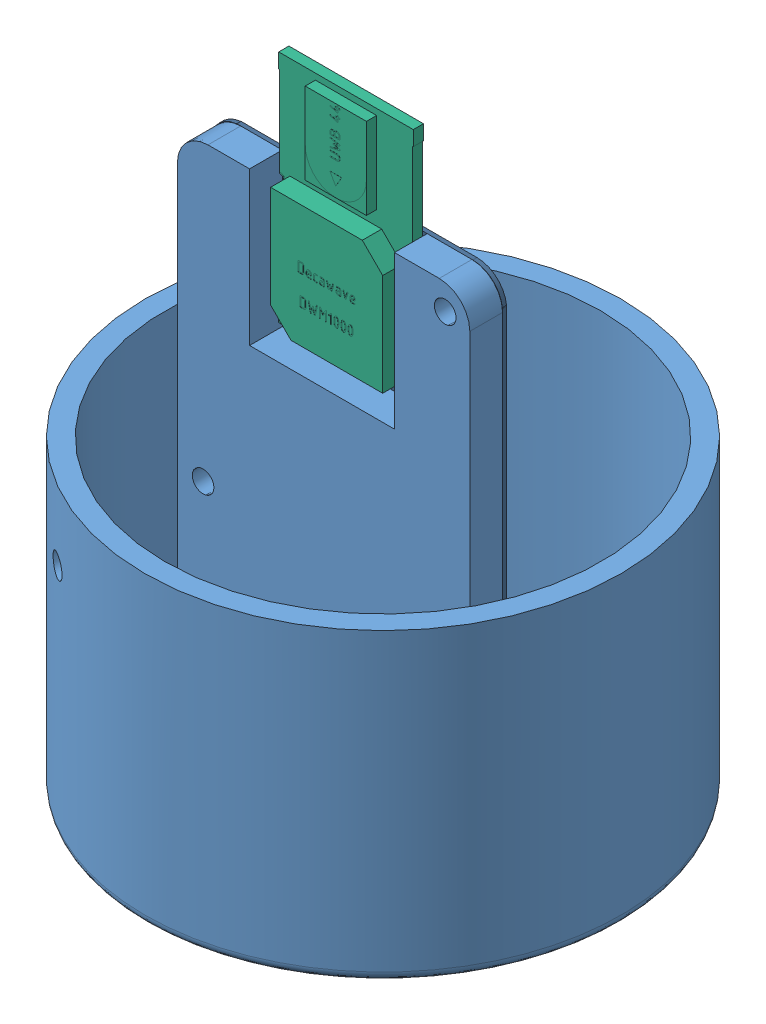
SolidWorks assembly 机器人顶部UWB基站装配, configuration 默认. Lengths in mm.
Overall size (46.7 61.16 46.7).
233 component instances, 28 part files, 0 mates.
Components (placement in the parent):
- UWB天线支架-TWR-1: UWB天线支架-TWR [默认] at (-22.1271 -22.7514 62) size (46.7 52 46.7)
- GeekUWB-TWR.step-1: GeekUWB-TWR.step [默认] at (68.161 -75.1454 64.2043) x (-1 0 0) z (0 0 -1) size (28.7 41.1 6.58)
  - R14.step-1: R14.step [默认] at origin size (0.5 1 0.35)
    - 5863272896.step-1: 5863272896.step [默认] at (77.2159 80.1371 0) x (0 1 0) z (0 0 1) size (1 0.5 0.35)
      - Terminal.step-1: Terminal.step [默认] at (-0.5 -0.25 0) size (0.25 0.5 0.35)
        - Open_CASCADE_STEP_translator_6.8_20.2.1.step-1: Open_CASCADE_STEP_translator_6.8_20.2.1.step [默认] at origin size (0.25 0.5 0.35)
      - Terminal.step-2: Terminal.step [默认] at (0.5 0.25 0) x (-1 0 0) z (0 0 1) size (0.25 0.5 0.35)
        - Open_CASCADE_STEP_translator_6.8_20.2.1.step-1: Open_CASCADE_STEP_translator_6.8_20.2.1.step [默认] at origin size (0.25 0.5 0.35)
      - Mid_Body.step-1: Mid_Body.step [默认] at (-0.5 -0.25 0) size (0.93 0.5 0.28)
      - Mark.step-1: Mark.step [默认] at (-0.25 -0.25 0.315) size (0.5 0.5 0.03)
  - C7.step-1: C7.step [默认] at origin size (1 0.5 0.5)
    - 5863272512.step-1: 5863272512.step [默认] at (78.8669 91.4399 0) x (-1 0 0) z (0 0 1) size (1 0.5 0.5)
      - Terminal-1.step-1: Terminal-1.step [默认] at (-0.5 -0.25 0) size (1 0.5 0.5)
        - Open_CASCADE_STEP_translator_6.8_54.1.1.step-1: Open_CASCADE_STEP_translator_6.8_54.1.1.step [默认] at origin size (0.25 0.5 0.5)
        - Open_CASCADE_STEP_translator_6.8_54.1.2.step-1: Open_CASCADE_STEP_translator_6.8_54.1.2.step [默认] at origin size (0.25 0.5 0.5)
      - Mid_Body-0.step-1: Mid_Body-0.step [默认] at (-0.5 -0.25 0) size (0.5 0.5 0.5)
        - Open_CASCADE_STEP_translator_6.8_54.2.1.step-1: Open_CASCADE_STEP_translator_6.8_54.2.1.step [默认] at origin size (0.5 0.5 0.5)
  - Y1.step-1: Y1.step [默认] at origin size (1.31 3.21 0.71)
    - 123123123.step-1: 123123123.step [默认] at (79.121 88.3921 0) x (0 1 0) z (0 0 1) size (3.21 1.31 0.71)
  - R7.step-1: R7.step [默认] at origin size (1 0.5 0.35)
    - 5863271360.step-1: 5863271360.step [默认] at (88.0109 97.2819 0) x (-1 0 0) z (0 0 1) size (1 0.5 0.35)
      - Terminal-2.step-1: Terminal-2.step [默认] at (-0.5 -0.25 0) size (0.25 0.5 0.35)
        - Open_CASCADE_STEP_translator_6.8_20.2.1-1.step-1: Open_CASCADE_STEP_translator_6.8_20.2.1-1.step [默认] at origin size (0.25 0.5 0.35)
      - Terminal-2.step-2: Terminal-2.step [默认] at (0.5 0.25 0) x (-1 0 0) z (0 0 1) size (0.25 0.5 0.35)
        - Open_CASCADE_STEP_translator_6.8_20.2.1-1.step-1: Open_CASCADE_STEP_translator_6.8_20.2.1-1.step [默认] at origin size (0.25 0.5 0.35)
      - Mid_Body-2.step-1: Mid_Body-2.step [默认] at (-0.5 -0.25 0) size (0.93 0.5 0.28)
      - Mark-3.step-1: Mark-3.step [默认] at (-0.25 -0.25 0.315) size (0.5 0.5 0.03)
  - R10.step-1: R10.step [默认] at origin size (1 0.5 0.35)
    - 5863271744.step-1: 5863271744.step [默认] at (101.3461 99.0601 0) x (1 0 0) z (0 0 1) size (1 0.5 0.35)
      - Terminal-3.step-1: Terminal-3.step [默认] at (-0.5 -0.25 0) size (0.25 0.5 0.35)
        - Open_CASCADE_STEP_translator_6.8_20.2.1-4.step-1: Open_CASCADE_STEP_translator_6.8_20.2.1-4.step [默认] at origin size (0.25 0.5 0.35)
      - Terminal-3.step-2: Terminal-3.step [默认] at (0.5 0.25 0) x (-1 0 0) z (0 0 1) size (0.25 0.5 0.35)
        - Open_CASCADE_STEP_translator_6.8_20.2.1-4.step-1: Open_CASCADE_STEP_translator_6.8_20.2.1-4.step [默认] at origin size (0.25 0.5 0.35)
      - Mid_Body-5.step-1: Mid_Body-5.step [默认] at (-0.5 -0.25 0) size (0.93 0.5 0.28)
      - Mark-6.step-1: Mark-6.step [默认] at (-0.25 -0.25 0.315) size (0.5 0.5 0.03)
  - R9.step-1: R9.step [默认] at origin size (1 0.5 0.35)
    - 5863271744.step-1: 5863271744.step [默认] at (101.3461 100.2031 0) x (1 0 0) z (0 0 1) size (1 0.5 0.35)
      - Terminal-3.step-1: Terminal-3.step [默认] at (-0.5 -0.25 0) size (0.25 0.5 0.35)
        - Open_CASCADE_STEP_translator_6.8_20.2.1-4.step-1: Open_CASCADE_STEP_translator_6.8_20.2.1-4.step [默认] at origin size (0.25 0.5 0.35)
      - Terminal-3.step-2: Terminal-3.step [默认] at (0.5 0.25 0) x (-1 0 0) z (0 0 1) size (0.25 0.5 0.35)
        - Open_CASCADE_STEP_translator_6.8_20.2.1-4.step-1: Open_CASCADE_STEP_translator_6.8_20.2.1-4.step [默认] at origin size (0.25 0.5 0.35)
      - Mid_Body-5.step-1: Mid_Body-5.step [默认] at (-0.5 -0.25 0) size (0.93 0.5 0.28)
      - Mark-6.step-1: Mark-6.step [默认] at (-0.25 -0.25 0.315) size (0.5 0.5 0.03)
  - R8.step-1: R8.step [默认] at origin size (1 0.5 0.35)
    - 5863271360.step-1: 5863271360.step [默认] at (82.0419 87.8839 0) x (-1 0 0) z (0 0 1) size (1 0.5 0.35)
      - Terminal-2.step-1: Terminal-2.step [默认] at (-0.5 -0.25 0) size (0.25 0.5 0.35)
        - Open_CASCADE_STEP_translator_6.8_20.2.1-1.step-1: Open_CASCADE_STEP_translator_6.8_20.2.1-1.step [默认] at origin size (0.25 0.5 0.35)
      - Terminal-2.step-2: Terminal-2.step [默认] at (0.5 0.25 0) x (-1 0 0) z (0 0 1) size (0.25 0.5 0.35)
        - Open_CASCADE_STEP_translator_6.8_20.2.1-1.step-1: Open_CASCADE_STEP_translator_6.8_20.2.1-1.step [默认] at origin size (0.25 0.5 0.35)
      - Mid_Body-2.step-1: Mid_Body-2.step [默认] at (-0.5 -0.25 0) size (0.93 0.5 0.28)
      - Mark-3.step-1: Mark-3.step [默认] at (-0.25 -0.25 0.315) size (0.5 0.5 0.03)
  - R6.step-1: R6.step [默认] at origin size (1 0.5 0.35)
    - 5863271744.step-1: 5863271744.step [默认] at (100.7111 89.2811 0) x (1 0 0) z (0 0 1) size (1 0.5 0.35)
      - Terminal-3.step-1: Terminal-3.step [默认] at (-0.5 -0.25 0) size (0.25 0.5 0.35)
        - Open_CASCADE_STEP_translator_6.8_20.2.1-4.step-1: Open_CASCADE_STEP_translator_6.8_20.2.1-4.step [默认] at origin size (0.25 0.5 0.35)
      - Terminal-3.step-2: Terminal-3.step [默认] at (0.5 0.25 0) x (-1 0 0) z (0 0 1) size (0.25 0.5 0.35)
        - Open_CASCADE_STEP_translator_6.8_20.2.1-4.step-1: Open_CASCADE_STEP_translator_6.8_20.2.1-4.step [默认] at origin size (0.25 0.5 0.35)
      - Mid_Body-5.step-1: Mid_Body-5.step [默认] at (-0.5 -0.25 0) size (0.93 0.5 0.28)
      - Mark-6.step-1: Mark-6.step [默认] at (-0.25 -0.25 0.315) size (0.5 0.5 0.03)
  - R5.step-1: R5.step [默认] at origin size (1 0.5 0.35)
    - 5863271744.step-1: 5863271744.step [默认] at (101.3461 101.3461 0) x (1 0 0) z (0 0 1) size (1 0.5 0.35)
      - Terminal-3.step-1: Terminal-3.step [默认] at (-0.5 -0.25 0) size (0.25 0.5 0.35)
        - Open_CASCADE_STEP_translator_6.8_20.2.1-4.step-1: Open_CASCADE_STEP_translator_6.8_20.2.1-4.step [默认] at origin size (0.25 0.5 0.35)
      - Terminal-3.step-2: Terminal-3.step [默认] at (0.5 0.25 0) x (-1 0 0) z (0 0 1) size (0.25 0.5 0.35)
        - Open_CASCADE_STEP_translator_6.8_20.2.1-4.step-1: Open_CASCADE_STEP_translator_6.8_20.2.1-4.step [默认] at origin size (0.25 0.5 0.35)
      - Mid_Body-5.step-1: Mid_Body-5.step [默认] at (-0.5 -0.25 0) size (0.93 0.5 0.28)
      - Mark-6.step-1: Mark-6.step [默认] at (-0.25 -0.25 0.315) size (0.5 0.5 0.03)
  - R2.step-1: R2.step [默认] at origin size (1 0.5 0.35)
    - 5863271744.step-1: 5863271744.step [默认] at (80.8991 85.4711 0) x (1 0 0) z (0 0 1) size (1 0.5 0.35)
      - Terminal-3.step-1: Terminal-3.step [默认] at (-0.5 -0.25 0) size (0.25 0.5 0.35)
        - Open_CASCADE_STEP_translator_6.8_20.2.1-4.step-1: Open_CASCADE_STEP_translator_6.8_20.2.1-4.step [默认] at origin size (0.25 0.5 0.35)
      - Terminal-3.step-2: Terminal-3.step [默认] at (0.5 0.25 0) x (-1 0 0) z (0 0 1) size (0.25 0.5 0.35)
        - Open_CASCADE_STEP_translator_6.8_20.2.1-4.step-1: Open_CASCADE_STEP_translator_6.8_20.2.1-4.step [默认] at origin size (0.25 0.5 0.35)
      - Mid_Body-5.step-1: Mid_Body-5.step [默认] at (-0.5 -0.25 0) size (0.93 0.5 0.28)
      - Mark-6.step-1: Mark-6.step [默认] at (-0.25 -0.25 0.315) size (0.5 0.5 0.03)
  - R3.step-1: R3.step [默认] at origin size (1 0.5 0.35)
    - 5863271744.step-1: 5863271744.step [默认] at (80.8991 84.4551 0) x (1 0 0) z (0 0 1) size (1 0.5 0.35)
      - Terminal-3.step-1: Terminal-3.step [默认] at (-0.5 -0.25 0) size (0.25 0.5 0.35)
        - Open_CASCADE_STEP_translator_6.8_20.2.1-4.step-1: Open_CASCADE_STEP_translator_6.8_20.2.1-4.step [默认] at origin size (0.25 0.5 0.35)
      - Terminal-3.step-2: Terminal-3.step [默认] at (0.5 0.25 0) x (-1 0 0) z (0 0 1) size (0.25 0.5 0.35)
        - Open_CASCADE_STEP_translator_6.8_20.2.1-4.step-1: Open_CASCADE_STEP_translator_6.8_20.2.1-4.step [默认] at origin size (0.25 0.5 0.35)
      - Mid_Body-5.step-1: Mid_Body-5.step [默认] at (-0.5 -0.25 0) size (0.93 0.5 0.28)
      - Mark-6.step-1: Mark-6.step [默认] at (-0.25 -0.25 0.315) size (0.5 0.5 0.03)
  - R1.step-1: R1.step [默认] at origin size (0.5 1 0.35)
    - 5863272896.step-1: 5863272896.step [默认] at (78.294 80.1531 0) x (0 1 0) z (0 0 1) size (1 0.5 0.35)
      - Terminal.step-1: Terminal.step [默认] at (-0.5 -0.25 0) size (0.25 0.5 0.35)
        - Open_CASCADE_STEP_translator_6.8_20.2.1.step-1: Open_CASCADE_STEP_translator_6.8_20.2.1.step [默认] at origin size (0.25 0.5 0.35)
      - Terminal.step-2: Terminal.step [默认] at (0.5 0.25 0) x (-1 0 0) z (0 0 1) size (0.25 0.5 0.35)
        - Open_CASCADE_STEP_translator_6.8_20.2.1.step-1: Open_CASCADE_STEP_translator_6.8_20.2.1.step [默认] at origin size (0.25 0.5 0.35)
      - Mid_Body.step-1: Mid_Body.step [默认] at (-0.5 -0.25 0) size (0.93 0.5 0.28)
      - Mark.step-1: Mark.step [默认] at (-0.25 -0.25 0.315) size (0.5 0.5 0.03)
  - R4.step-1: R4.step [默认] at origin size (1 0.5 0.35)
    - 5863271744.step-1: 5863271744.step [默认] at (80.8991 83.4391 0) x (1 0 0) z (0 0 1) size (1 0.5 0.35)
      - Terminal-3.step-1: Terminal-3.step [默认] at (-0.5 -0.25 0) size (0.25 0.5 0.35)
        - Open_CASCADE_STEP_translator_6.8_20.2.1-4.step-1: Open_CASCADE_STEP_translator_6.8_20.2.1-4.step [默认] at origin size (0.25 0.5 0.35)
      - Terminal-3.step-2: Terminal-3.step [默认] at (0.5 0.25 0) x (-1 0 0) z (0 0 1) size (0.25 0.5 0.35)
        - Open_CASCADE_STEP_translator_6.8_20.2.1-4.step-1: Open_CASCADE_STEP_translator_6.8_20.2.1-4.step [默认] at origin size (0.25 0.5 0.35)
      - Mid_Body-5.step-1: Mid_Body-5.step [默认] at (-0.5 -0.25 0) size (0.93 0.5 0.28)
      - Mark-6.step-1: Mark-6.step [默认] at (-0.25 -0.25 0.315) size (0.5 0.5 0.03)
  - R13.step-1: R13.step [默认] at origin size (1 0.5 0.35)
    - 5863271360.step-1: 5863271360.step [默认] at (98.8059 91.4399 0) x (-1 0 0) z (0 0 1) size (1 0.5 0.35)
      - Terminal-2.step-1: Terminal-2.step [默认] at (-0.5 -0.25 0) size (0.25 0.5 0.35)
        - Open_CASCADE_STEP_translator_6.8_20.2.1-1.step-1: Open_CASCADE_STEP_translator_6.8_20.2.1-1.step [默认] at origin size (0.25 0.5 0.35)
      - Terminal-2.step-2: Terminal-2.step [默认] at (0.5 0.25 0) x (-1 0 0) z (0 0 1) size (0.25 0.5 0.35)
        - Open_CASCADE_STEP_translator_6.8_20.2.1-1.step-1: Open_CASCADE_STEP_translator_6.8_20.2.1-1.step [默认] at origin size (0.25 0.5 0.35)
      - Mid_Body-2.step-1: Mid_Body-2.step [默认] at (-0.5 -0.25 0) size (0.93 0.5 0.28)
      - Mark-3.step-1: Mark-3.step [默认] at (-0.25 -0.25 0.315) size (0.5 0.5 0.03)
  - R12.step-1: R12.step [默认] at origin size (0.5 1 0.35)
    - 5863271552.step-1: 5863271552.step [默认] at (101.2191 86.7769 0) x (0 -1 0) z (0 0 1) size (1 0.5 0.35)
      - Terminal-4.step-1: Terminal-4.step [默认] at (-0.5 -0.25 0) size (0.25 0.5 0.35)
        - Open_CASCADE_STEP_translator_6.8_20.2.1-7.step-1: Open_CASCADE_STEP_translator_6.8_20.2.1-7.step [默认] at origin size (0.25 0.5 0.35)
      - Terminal-4.step-2: Terminal-4.step [默认] at (0.5 0.25 0) x (-1 0 0) z (0 0 1) size (0.25 0.5 0.35)
        - Open_CASCADE_STEP_translator_6.8_20.2.1-7.step-1: Open_CASCADE_STEP_translator_6.8_20.2.1-7.step [默认] at origin size (0.25 0.5 0.35)
      - Mid_Body-8.step-1: Mid_Body-8.step [默认] at (-0.5 -0.25 0) size (0.93 0.5 0.28)
      - Mark-9.step-1: Mark-9.step [默认] at (-0.25 -0.25 0.315) size (0.5 0.5 0.03)
  - R11.step-1: R11.step [默认] at origin size (1 0.5 0.35)
    - 5863271744.step-1: 5863271744.step [默认] at (90.9941 97.3479 0) x (1 0 0) z (0 0 1) size (1 0.5 0.35)
      - Terminal-3.step-1: Terminal-3.step [默认] at (-0.5 -0.25 0) size (0.25 0.5 0.35)
        - Open_CASCADE_STEP_translator_6.8_20.2.1-4.step-1: Open_CASCADE_STEP_translator_6.8_20.2.1-4.step [默认] at origin size (0.25 0.5 0.35)
      - Terminal-3.step-2: Terminal-3.step [默认] at (0.5 0.25 0) x (-1 0 0) z (0 0 1) size (0.25 0.5 0.35)
        - Open_CASCADE_STEP_translator_6.8_20.2.1-4.step-1: Open_CASCADE_STEP_translator_6.8_20.2.1-4.step [默认] at origin size (0.25 0.5 0.35)
      - Mid_Body-5.step-1: Mid_Body-5.step [默认] at (-0.5 -0.25 0) size (0.93 0.5 0.28)
      - Mark-6.step-1: Mark-6.step [默认] at (-0.25 -0.25 0.315) size (0.5 0.5 0.03)
  - D4.step-1: D4.step [默认] at origin size (1.01 0.5 0.45)
    - User_Library-led_0402LED0402_red_.step-1: User_Library-led_0402LED0402_red_.step [默认] at (98.6791 89.281 0) x (1 0 0) z (0 0 1) size (1.01 0.5 0.45)
  - D1.step-1: D1.step [默认] at origin size (1.01 0.5 0.45)
    - User_Library-led_0402LED0402_red_.step-1: User_Library-led_0402LED0402_red_.step [默认] at (99.3141 100.203 0) x (1 0 0) z (0 0 1) size (1.01 0.5 0.45)
  - D2.step-1: D2.step [默认] at origin size (1.01 0.5 0.45)
    - User_Library-led_0402LED0402_red_.step-1: User_Library-led_0402LED0402_red_.step [默认] at (99.3141 99.06 0) x (1 0 0) z (0 0 1) size (1.01 0.5 0.45)
  - D3.step-1: D3.step [默认] at origin size (1.01 0.5 0.45)
    - User_Library-led_0402LED0402_red_.step-1: User_Library-led_0402LED0402_red_.step [默认] at (99.3141 101.346 0) x (1 0 0) z (0 0 1) size (1.01 0.5 0.45)
  - C5.step-1: C5.step [默认] at origin size (0.5 1 0.5)
    - 5863270784.step-1: 5863270784.step [默认] at (98.6791 96.5199 0) x (0 -1 0) z (0 0 1) size (1 0.5 0.5)
      - Terminal-5.step-1: Terminal-5.step [默认] at (-0.5 -0.25 0) size (1 0.5 0.5)
        - Open_CASCADE_STEP_translator_6.8_54.1.1-10.step-1: Open_CASCADE_STEP_translator_6.8_54.1.1-10.step [默认] at origin size (0.25 0.5 0.5)
        - Open_CASCADE_STEP_translator_6.8_54.1.2-11.step-1: Open_CASCADE_STEP_translator_6.8_54.1.2-11.step [默认] at origin size (0.25 0.5 0.5)
      - Mid_Body-1.step-1: Mid_Body-1.step [默认] at (-0.5 -0.25 0) size (0.5 0.5 0.5)
        - Open_CASCADE_STEP_translator_6.8_54.2.1-12.step-1: Open_CASCADE_STEP_translator_6.8_54.2.1-12.step [默认] at origin size (0.5 0.5 0.5)
  - C6.step-1: C6.step [默认] at origin size (1 0.5 0.5)
    - 5863272512.step-1: 5863272512.step [默认] at (82.0419 88.9126 0) x (-1 0 0) z (0 0 1) size (1 0.5 0.5)
      - Terminal-1.step-1: Terminal-1.step [默认] at (-0.5 -0.25 0) size (1 0.5 0.5)
        - Open_CASCADE_STEP_translator_6.8_54.1.1.step-1: Open_CASCADE_STEP_translator_6.8_54.1.1.step [默认] at origin size (0.25 0.5 0.5)
        - Open_CASCADE_STEP_translator_6.8_54.1.2.step-1: Open_CASCADE_STEP_translator_6.8_54.1.2.step [默认] at origin size (0.25 0.5 0.5)
      - Mid_Body-0.step-1: Mid_Body-0.step [默认] at (-0.5 -0.25 0) size (0.5 0.5 0.5)
        - Open_CASCADE_STEP_translator_6.8_54.2.1.step-1: Open_CASCADE_STEP_translator_6.8_54.2.1.step [默认] at origin size (0.5 0.5 0.5)
  - C4.step-1: C4.step [默认] at origin size (1.6 0.81 0.81)
    - C0603_3D.step-1: C0603_3D.step [默认] at (100.7109 96.3929 0) x (-1 0 0) z (0 0 1) size (1.6 0.81 0.81)
  - C3.step-1: C3.step [默认] at origin size (0.5 1 0.5)
    - 5863270784.step-1: 5863270784.step [默认] at (100.0761 86.7849 0) x (0 -1 0) z (0 0 1) size (1 0.5 0.5)
      - Terminal-5.step-1: Terminal-5.step [默认] at (-0.5 -0.25 0) size (1 0.5 0.5)
        - Open_CASCADE_STEP_translator_6.8_54.1.1-10.step-1: Open_CASCADE_STEP_translator_6.8_54.1.1-10.step [默认] at origin size (0.25 0.5 0.5)
        - Open_CASCADE_STEP_translator_6.8_54.1.2-11.step-1: Open_CASCADE_STEP_translator_6.8_54.1.2-11.step [默认] at origin size (0.25 0.5 0.5)
      - Mid_Body-1.step-1: Mid_Body-1.step [默认] at (-0.5 -0.25 0) size (0.5 0.5 0.5)
        - Open_CASCADE_STEP_translator_6.8_54.2.1-12.step-1: Open_CASCADE_STEP_translator_6.8_54.2.1-12.step [默认] at origin size (0.5 0.5 0.5)
  - C2.step-1: C2.step [默认] at origin size (0.81 1.6 0.81)
    - C0603_3D.step-1: C0603_3D.step [默认] at (98.5521 86.9949 0) x (0 -1 0) z (0 0 1) size (1.6 0.81 0.81)
  - C1.step-1: C1.step [默认] at origin size (1.6 0.81 0.81)
    - C0603_3D.step-1: C0603_3D.step [默认] at (78.9939 92.8369 0) x (-1 0 0) z (0 0 1) size (1.6 0.81 0.81)
  - USB.step-1: USB.step [默认] at origin size (8.96 7.76 4.27)
    - 1.step-1: 1.step [默认] at (98.1049 122.7063 3.5) x (1 0 0) z (0 0 -1) size (8.96 7.76 4.27)
  - U3.step-1: U3.step [默认] at origin size (13.2 23 2.9)
    - DWM1000_Module.step-1: DWM1000_Module.step [默认] at (90.301 102.0509 -0.4115) x (-1 0 0) z (0 -1 0) size (13.2 2.9 23)
  - U2.step-1: U2.step [默认] at origin size (2.9 2.8 1.2)
    - PCB1.step-1: PCB1.step [默认] at (80.4724 95.505 0) x (0 1 0) z (0 0 1) size (2.8 2.9 1.2)
  - U1.step-1: U1.step [默认] at origin size (12.01 12.01 1.45)
    - LQFP64-10x10.step-1: LQFP64-10x10.step [默认] at (90.2971 89.5349 0) x (0 -1 0) z (0 0 1) size (12.01 12.01 1.45)
      - LQFP64-10X10_1_AF0_ASM.step-1: LQFP64-10X10_1_AF0_ASM.step [默认] at origin size (12.01 12.01 1.45)
        - _0_25_100.step-1: _0_25_100.step [默认] at (-5 2.75 0.75) x (0 1 0) z (0 0 1) size (0.25 1 0.8)
        - _0_25_100.step-2: _0_25_100.step [默认] at (5 -1.25 0.75) x (0 -1 0) z (0 0 1) size (0.25 1 0.8)
        - _0_25_100.step-3: _0_25_100.step [默认] at (-0.75 5 0.75) size (0.25 1 0.8)
        - _0_25_100.step-4: _0_25_100.step [默认] at (-5 -2.75 0.75) x (0 1 0) z (0 0 1) size (0.25 1 0.8)
        - _0_25_100.step-5: _0_25_100.step [默认] at (-2.75 -5 0.75) x (-1 0 0) z (0 0 1) size (0.25 1 0.8)
        - _0_25_100.step-6: _0_25_100.step [默认] at (2.75 -5 0.75) x (-1 0 0) z (0 0 1) size (0.25 1 0.8)
        - _0_25_100.step-7: _0_25_100.step [默认] at (-5 3.75 0.75) x (0 1 0) z (0 0 1) size (0.25 1 0.8)
        - _0_25_100.step-8: _0_25_100.step [默认] at (5 -2.25 0.75) x (0 -1 0) z (0 0 1) size (0.25 1 0.8)
        - _0_25_100.step-9: _0_25_100.step [默认] at (0.25 5 0.75) size (0.25 1 0.8)
        - _0_25_100.step-10: _0_25_100.step [默认] at (-5 -1.75 0.75) x (0 1 0) z (0 0 1) size (0.25 1 0.8)
        - _0_25_100.step-11: _0_25_100.step [默认] at (5 3.25 0.75) x (0 -1 0) z (0 0 1) size (0.25 1 0.8)
        - _0_25_100.step-12: _0_25_100.step [默认] at (-0.25 -5 0.75) x (-1 0 0) z (0 0 1) size (0.25 1 0.8)
        - _0_25_100.step-13: _0_25_100.step [默认] at (5 -3.25 0.75) x (0 -1 0) z (0 0 1) size (0.25 1 0.8)
        - _0_25_100.step-14: _0_25_100.step [默认] at (1.25 5 0.75) size (0.25 1 0.8)
        - _0_25_100.step-15: _0_25_100.step [默认] at (-5 -0.75 0.75) x (0 1 0) z (0 0 1) size (0.25 1 0.8)
        - _0_25_100.step-16: _0_25_100.step [默认] at (5 2.25 0.75) x (0 -1 0) z (0 0 1) size (0.25 1 0.8)
        - _0_25_100.step-17: _0_25_100.step [默认] at (-3.25 -5 0.75) x (-1 0 0) z (0 0 1) size (0.25 1 0.8)
        - _0_25_100.step-18: _0_25_100.step [默认] at (2.25 -5 0.75) x (-1 0 0) z (0 0 1) size (0.25 1 0.8)
        - _0_25_100.step-19: _0_25_100.step [默认] at (2.25 5 0.75) size (0.25 1 0.8)
        - _0_25_100.step-20: _0_25_100.step [默认] at (-5 0.25 0.75) x (0 1 0) z (0 0 1) size (0.25 1 0.8)
        - _0_25_100.step-21: _0_25_100.step [默认] at (5 1.25 0.75) x (0 -1 0) z (0 0 1) size (0.25 1 0.8)
        - _0_25_100.step-22: _0_25_100.step [默认] at (-3.25 5 0.75) size (0.25 1 0.8)
        - _0_25_100.step-23: _0_25_100.step [默认] at (-0.75 -5 0.75) x (-1 0 0) z (0 0 1) size (0.25 1 0.8)
        - _0_25_100.step-24: _0_25_100.step [默认] at (3.25 5 0.75) size (0.25 1 0.8)
        - _0_25_100.step-25: _0_25_100.step [默认] at (-5 1.25 0.75) x (0 1 0) z (0 0 1) size (0.25 1 0.8)
        - _0_25_100.step-26: _0_25_100.step [默认] at (5 0.25 0.75) x (0 -1 0) z (0 0 1) size (0.25 1 0.8)
        - _0_25_100.step-27: _0_25_100.step [默认] at (-2.25 5 0.75) size (0.25 1 0.8)
        - _0_25_100.step-28: _0_25_100.step [默认] at (-3.75 -5 0.75) x (-1 0 0) z (0 0 1) size (0.25 1 0.8)
        - _0_25_100.step-29: _0_25_100.step [默认] at (1.75 -5 0.75) x (-1 0 0) z (0 0 1) size (0.25 1 0.8)
        - _0_25_100.step-30: _0_25_100.step [默认] at (-5 2.25 0.75) x (0 1 0) z (0 0 1) size (0.25 1 0.8)
        - _0_25_100.step-31: _0_25_100.step [默认] at (5 -0.75 0.75) x (0 -1 0) z (0 0 1) size (0.25 1 0.8)
        - _0_25_100.step-32: _0_25_100.step [默认] at (-1.25 5 0.75) size (0.25 1 0.8)
        - _0_25_100.step-33: _0_25_100.step [默认] at (-5 -3.25 0.75) x (0 1 0) z (0 0 1) size (0.25 1 0.8)
        - _0_25_100.step-34: _0_25_100.step [默认] at (-1.25 -5 0.75) x (-1 0 0) z (0 0 1) size (0.25 1 0.8)
        - LQFP64_10X10___A.step-1: LQFP64_10X10___A.step [默认] at origin size (10 10 1.4)
        - _0_25_100.step-35: _0_25_100.step [默认] at (-5 3.25 0.75) x (0 1 0) z (0 0 1) size (0.25 1 0.8)
        - _0_25_100.step-36: _0_25_100.step [默认] at (5 -1.75 0.75) x (0 -1 0) z (0 0 1) size (0.25 1 0.8)
        - _0_25_100.step-37: _0_25_100.step [默认] at (-0.25 5 0.75) size (0.25 1 0.8)
        - _0_25_100.step-38: _0_25_100.step [默认] at (-5 -2.25 0.75) x (0 1 0) z (0 0 1) size (0.25 1 0.8)
        - _0_25_100.step-39: _0_25_100.step [默认] at (5 3.75 0.75) x (0 -1 0) z (0 0 1) size (0.25 1 0.8)
        - _0_25_100.step-40: _0_25_100.step [默认] at (1.25 -5 0.75) x (-1 0 0) z (0 0 1) size (0.25 1 0.8)
        - _0_25_100.step-41: _0_25_100.step [默认] at (5 -2.75 0.75) x (0 -1 0) z (0 0 1) size (0.25 1 0.8)
        - _0_25_100.step-42: _0_25_100.step [默认] at (0.75 5 0.75) size (0.25 1 0.8)
        - _0_25_100.step-43: _0_25_100.step [默认] at (-5 -1.25 0.75) x (0 1 0) z (0 0 1) size (0.25 1 0.8)
        - _0_25_100.step-44: _0_25_100.step [默认] at (5 2.75 0.75) x (0 -1 0) z (0 0 1) size (0.25 1 0.8)
        - _0_25_100.step-45: _0_25_100.step [默认] at (-1.75 -5 0.75) x (-1 0 0) z (0 0 1) size (0.25 1 0.8)
        - _0_25_100.step-46: _0_25_100.step [默认] at (3.75 -5 0.75) x (-1 0 0) z (0 0 1) size (0.25 1 0.8)
        - _0_25_100.step-47: _0_25_100.step [默认] at (5 -3.75 0.75) x (0 -1 0) z (0 0 1) size (0.25 1 0.8)
        - _0_25_100.step-48: _0_25_100.step [默认] at (1.75 5 0.75) size (0.25 1 0.8)
        - _0_25_100.step-49: _0_25_100.step [默认] at (-5 -0.25 0.75) x (0 1 0) z (0 0 1) size (0.25 1 0.8)
        - _0_25_100.step-50: _0_25_100.step [默认] at (5 1.75 0.75) x (0 -1 0) z (0 0 1) size (0.25 1 0.8)
        - _0_25_100.step-51: _0_25_100.step [默认] at (-3.75 5 0.75) size (0.25 1 0.8)
        - _0_25_100.step-52: _0_25_100.step [默认] at (0.75 -5 0.75) x (-1 0 0) z (0 0 1) size (0.25 1 0.8)
        - _0_25_100.step-53: _0_25_100.step [默认] at (2.75 5 0.75) size (0.25 1 0.8)
        - _0_25_100.step-54: _0_25_100.step [默认] at (-5 0.75 0.75) x (0 1 0) z (0 0 1) size (0.25 1 0.8)
        - _0_25_100.step-55: _0_25_100.step [默认] at (5 0.75 0.75) x (0 -1 0) z (0 0 1) size (0.25 1 0.8)
        - _0_25_100.step-56: _0_25_100.step [默认] at (-2.75 5 0.75) size (0.25 1 0.8)
        - _0_25_100.step-57: _0_25_100.step [默认] at (-2.25 -5 0.75) x (-1 0 0) z (0 0 1) size (0.25 1 0.8)
        - _0_25_100.step-58: _0_25_100.step [默认] at (3.25 -5 0.75) x (-1 0 0) z (0 0 1) size (0.25 1 0.8)
        - _0_25_100.step-59: _0_25_100.step [默认] at (3.75 5 0.75) size (0.25 1 0.8)
        - _0_25_100.step-60: _0_25_100.step [默认] at (-5 1.75 0.75) x (0 1 0) z (0 0 1) size (0.25 1 0.8)
        - _0_25_100.step-61: _0_25_100.step [默认] at (5 -0.25 0.75) x (0 -1 0) z (0 0 1) size (0.25 1 0.8)
        - _0_25_100.step-62: _0_25_100.step [默认] at (-1.75 5 0.75) size (0.25 1 0.8)
        - _0_25_100.step-63: _0_25_100.step [默认] at (-5 -3.75 0.75) x (0 1 0) z (0 0 1) size (0.25 1 0.8)
        - _0_25_100.step-64: _0_25_100.step [默认] at (0.25 -5 0.75) x (-1 0 0) z (0 0 1) size (0.25 1 0.8)
  - Board.step-1: Board.step [默认] at origin size (28.7 31.37 0.41)
